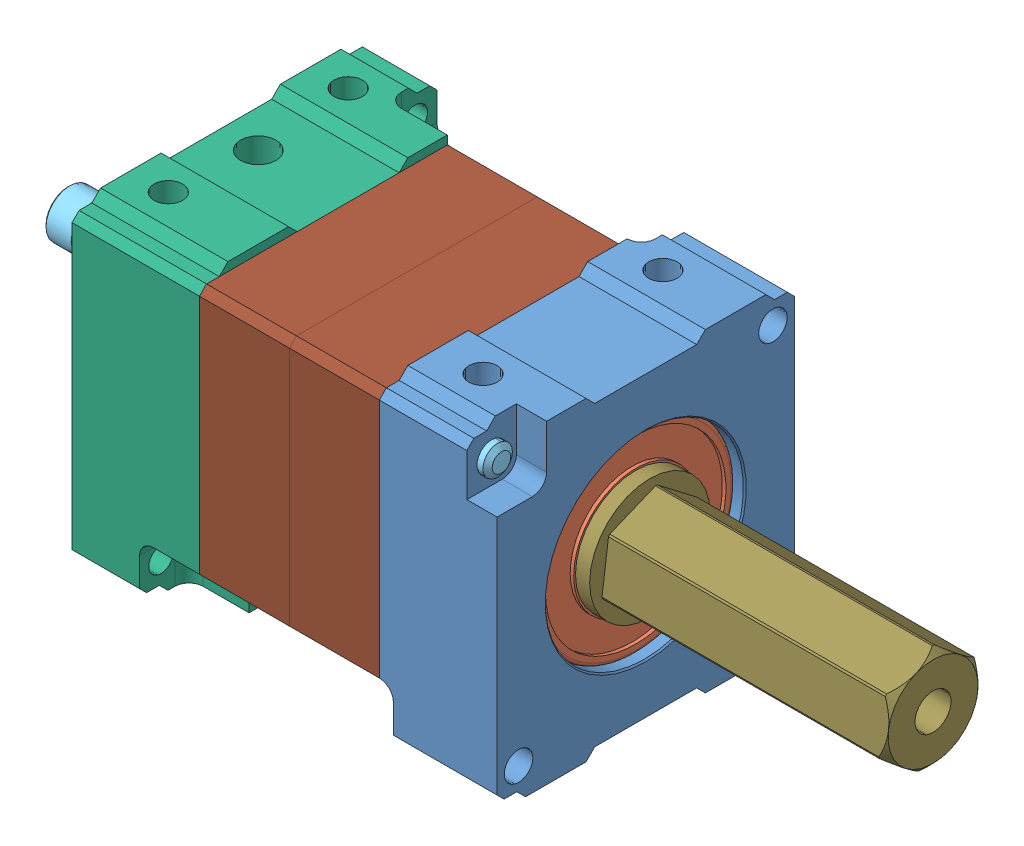
SolidWorks assembly VEX Gearbox, configuration Default. Lengths in mm.
Overall size (104.66 49.05 49.3).
31 component instances, 12 part files, 2 mates.
Components (placement in the parent):
- 217-2625-026 Rev1-1: 217-2625-026 Rev1 [Default] at (-6.5 22.225 0) x (0 -1 0) z (-1 0 0) size (44.45 42 18.13)
- 217-2742-001 Rev4-1: 217-2742-001 Rev4 [Default] at (0.2002 22.225 0) x (1 0 0) z (0 -0.092627 0.995701) size (7 28 28)
- 217-2742-001 Rev4-2: 217-2742-001 Rev4 [Default] at (8.2002 22.225 0) size (7 28 28)
- 217-2625-017 Rev1_9714K61-1: 217-2625-017 Rev1_9714K61 [Default] at (7.42 22.3002 -0.342) x (0 0.56703 0.823697) z (0 -0.823697 0.56703) size (28.51 4.98 30.18)
- 217-2625-018 Rev1_98541A410-1: 217-2625-018 Rev1_98541A410 [Default] at (-0.7046 22.225 0) x (1 0 0) z (0 -0.017452 0.999848) size (1 19.6 17.4)
- 832-2250-Base-Kit-Screw_SSA0832-0500ZC-1: 832-2250-Base-Kit-Screw_SSA0832-0500ZC [Default] at (-43.4 4.725 -17.5) x (0 -0.767799 -0.640691) z (0 0.640691 -0.767799) size (6.73 61.21 6.73)
- 832-2250-Base-Kit-Screw_SSA0832-0500ZC-2: 832-2250-Base-Kit-Screw_SSA0832-0500ZC [Default] at (-43.4 39.725 17.5) x (0 0.961307 0.275478) z (0 -0.275478 0.961307) size (6.73 61.21 6.73)
- 217-2625-025 Rev1-1: 217-2625-025 Rev1 [Default] at (-35.9 22.225 0) x (0 -1 0) z (-1 0 0) size (44.45 42 18)
- 217-2820 Rev1_Public-1: 217-2820 Rev1_Public [Default] at (-4.6546 22.225 0) x (0 -0.456494 0.889726) z (-1 0 0) size (39.26 38.9 17.4)
  - 217-2625-100-1: 217-2625-100 [Default] at origin size (39.26 38.9 12.7)
    - 217-2625-008 Rev1-1: 217-2625-008 Rev1 [Default] at origin size (34.7 34.7 4.7)
    - 217-2625-010 Rev1-1: 217-2625-010 Rev1 [Default] at (0 10.193 3.65) x (0.999813 0.019336 0) z (0 0 1) size (4 4 12)
    - 217-2625-010 Rev1-2: 217-2625-010 Rev1 [Default] at (8.691 -5.3258 3.65) size (4 4 12)
    - 217-2625-010 Rev1-3: 217-2625-010 Rev1 [Default] at (-8.691 -5.3258 3.65) size (4 4 12)
    - 217-2625-005 Rev1_Planet_Revolving_Follower01-1: 217-2625-005 Rev1_Planet_Revolving_Follower01 [Default] at (8.691 -5.3258 6.35) x (0.932816 0.360354 0) z (0 0 1) size (16.91 16.92 8)
    - 217-2625-005 Rev1_Planet_Revolving_Follower01-2: 217-2625-005 Rev1_Planet_Revolving_Follower01 [Default] at (-8.691 -5.3258 6.35) x (-0.932788 -0.360426 0) z (0 0 1) size (16.91 16.92 8)
    - 217-2625-005 Rev1_Planet_Revolving_Follower01-3: 217-2625-005 Rev1_Planet_Revolving_Follower01 [Default] at (0 10.193 6.35) x (0.893583 0.448898 0) z (0 0 1) size (16.91 16.92 8)
  - 217-2625-007 Rev1_Public-1: 217-2625-007 Rev1_Public [Default] at (0 0 6.7) x (0.992772 0.120019 0) z (0 0 1) size (14.49 14.49 12.72)
- 217-2816-001 Rev1-1: 217-2816-001 Rev1 [Default] at (-6.35 22.225 0) x (0 -1 0) z (1 0 0) size (42 42 14.5)
- 217-2820 Rev1_Public-2: 217-2820 Rev1_Public [Default] at (-17.15 22.225 0) x (0 0.184082 0.982911) z (-1 0 0) size (39.26 38.9 17.4)
  - 217-2625-100-1: 217-2625-100 [Default] at origin size (39.26 38.9 12.7)
    - 217-2625-008 Rev1-1: 217-2625-008 Rev1 [Default] at origin size (34.7 34.7 4.7)
    - 217-2625-010 Rev1-1: 217-2625-010 Rev1 [Default] at (0 10.193 3.65) x (0.999813 0.019336 0) z (0 0 1) size (4 4 12)
    - 217-2625-010 Rev1-2: 217-2625-010 Rev1 [Default] at (8.691 -5.3258 3.65) size (4 4 12)
    - 217-2625-010 Rev1-3: 217-2625-010 Rev1 [Default] at (-8.691 -5.3258 3.65) size (4 4 12)
    - 217-2625-005 Rev1_Planet_Revolving_Follower01-1: 217-2625-005 Rev1_Planet_Revolving_Follower01 [Default] at (8.691 -5.3258 6.35) x (0.932816 0.360354 0) z (0 0 1) size (16.91 16.92 8)
    - 217-2625-005 Rev1_Planet_Revolving_Follower01-2: 217-2625-005 Rev1_Planet_Revolving_Follower01 [Default] at (-8.691 -5.3258 6.35) x (-0.932788 -0.360426 0) z (0 0 1) size (16.91 16.92 8)
    - 217-2625-005 Rev1_Planet_Revolving_Follower01-3: 217-2625-005 Rev1_Planet_Revolving_Follower01 [Default] at (0 10.193 6.35) x (0.893583 0.448898 0) z (0 0 1) size (16.91 16.92 8)
  - 217-2625-007 Rev1_Public-1: 217-2625-007 Rev1_Public [Default] at (0 0 6.7) x (0.992772 0.120019 0) z (0 0 1) size (14.49 14.49 12.72)
- 217-2816-001 Rev1-2: 217-2816-001 Rev1 [Default] at (-19.05 22.225 0) x (0 -1 0) z (1 0 0) size (42 42 14.5)
- Hex Output Shaft-1: Hex Output Shaft [Default] at (7.4478 22.225 0) x (0 -0.924225 -0.381849) z (1 0 0) size (17 17 64.13)
Mates (geometry in assembly coordinates):
- Concentric1: concentric: cylinder of 217-2742-001 Rev4-2 through (8.2002 22.225 0) axis (-1 0 0) radius 7.5; cylinder of Hex Output Shaft-1 through (17.2002 22.225 0) axis (-1 0 0) radius 7.4955
- Coincident1: coincident anti-aligned: plane of 217-2742-001 Rev4-2 through (15.2002 29.725 0) normal (1 0 0); plane of Hex Output Shaft-1 through (15.2002 22.225 0) normal (-1 0 0)
